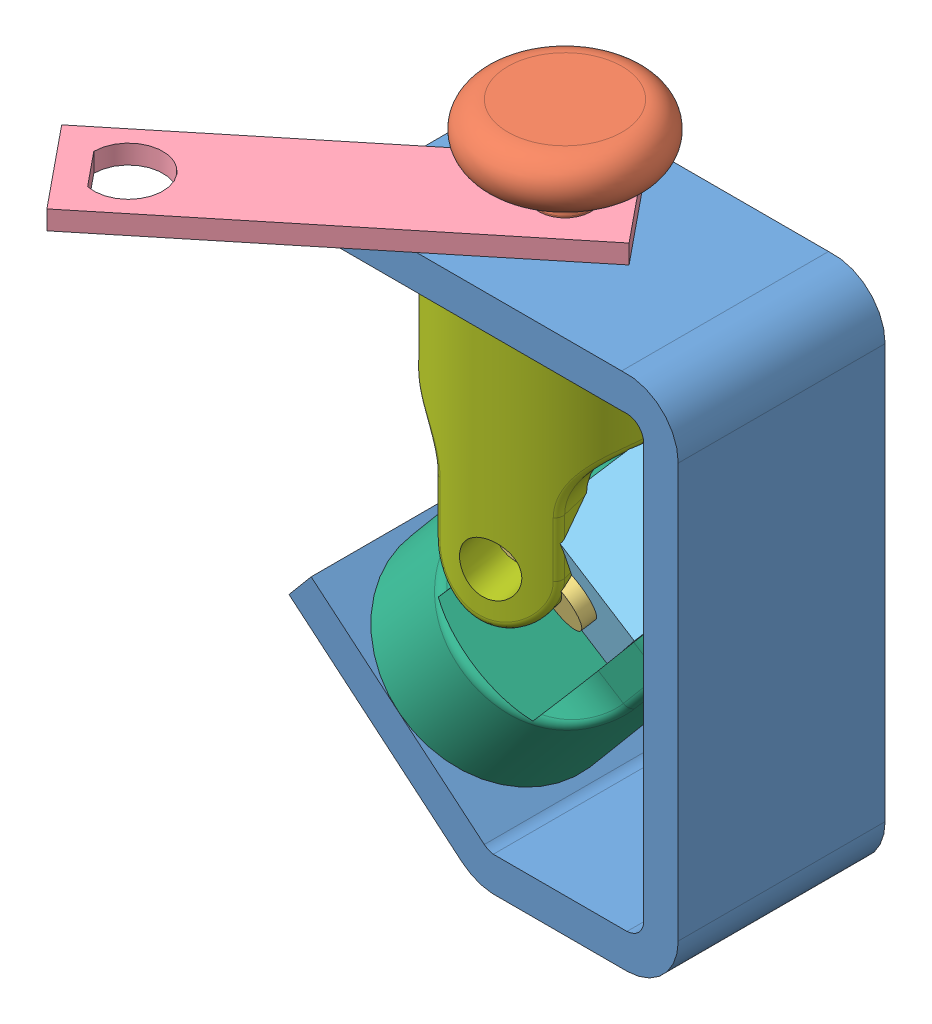
SolidWorks assembly Assem1, configuration Default. Lengths in mm.
Overall size (97.73 122.57 72.66).
10 component instances, 7 part files, 20 mates.
Components (placement in the parent):
- Taran (3)-1: Taran (3) [Default] at (30.1828 89.4752 48.9839) size (71.68 95.29 38.1)
- Taran (4)-1: Taran (4) [Default] at (54.6828 86.6252 68.0339) x (-0.908705 0 -0.41744) z (0.41744 0 -0.908705) size (30.54 21.91 30.54)
- Taran (6)-1: Taran (6) [Default] at (65.1662 39.4433 79.6676) x (-0.540596 -0.746524 -0.387889) z (0.177871 0.349222 -0.920003) size (9.52 9.52 12.7)
- Taran (7)-1: Taran (7) [Default] at (55.909 89.4752 54.7431) x (-0.77497 0 0.631998) z (-0.631998 0 -0.77497) size (76.2 3.5 19.05)
- Taran (8)-1: Taran (8) [Default] at (73.7349 50.8145 71.8958) x (0.177871 0.349222 -0.920003) z (-0.762547 0.639853 0.095452) size (20.32 20.32 20.32)
- t9-1: t9 [Default] at (54.7654 28.7835 68.0339) x (0.07312 -0.061355 0.995434) z (0.762547 -0.639853 -0.095452) size (38.96 67.63 38.1)
- t11-1: t11 [Default] at (54.6828 64.7052 68.0339) x (0.972965 0 -0.230951) z (0.230951 0 0.972965) size (38.96 47.63 38.1)
- Taran (6)-2: Taran (6) [Default] at (69.6841 48.3135 56.2995) x (-0.330869 0.901704 0.278307) z (-0.177871 -0.349222 0.920003) size (9.52 9.52 12.7)
- Taran (6)-3: Taran (6) [Default] at (54.0962 45.0252 65.5626) x (-0.665713 -0.729285 0.158019) z (0.230951 0 0.972965) size (9.52 9.52 12.7)
- Taran (6)-4: Taran (6) [Default] at (55.2694 45.0252 70.5052) x (-0.342478 -0.936002 0.081293) z (-0.230951 0 -0.972965) size (9.52 9.52 12.7)
Mates (geometry in assembly coordinates):
- Concentric1: concentric aligned: cylinder of Taran (4)-1 through (54.6828 86.6252 68.0339) axis (0 -1 0) radius 2.38; cylinder of Taran (7)-1 through (54.6828 92.9752 68.0339) axis (0 -1 0) radius 2.37
- Concentric2: concentric aligned: circle of Taran (3)-1; circle of t9-1
- Coincident1: coincident anti-aligned: plane of Taran (3)-1 through (58.8666 1.2966 87.0839) normal (0.642788 0.766044 0); circle of t9-1
- Concentric3: concentric aligned: circle of Taran (3)-1; circle of Taran (7)-1
- Concentric4: concentric aligned: circle of Taran (3)-1; circle of Taran (7)-1
- Coincident2: coincident anti-aligned: plane of Taran (3)-1 through (30.1828 89.4752 87.0839) normal (0 1 0); plane of Taran (7)-1 through (55.909 89.4752 54.7431) normal (0 -1 0)
- Concentric5: concentric aligned: cylinder of Taran (4)-1 through (54.6828 86.6252 68.0339) axis (0 -1 0) radius 2.38; cylinder of Taran (7)-1 through (54.6828 92.9752 68.0339) axis (0 -1 0) radius 2.37
- Coincident3: coincident anti-aligned: plane of Taran (4)-1 through (52.5201 92.9752 67.0404) normal (0 -1 0); plane of Taran (7)-1 through (55.909 92.9752 54.7431) normal (0 1 0)
- Concentric8: concentric aligned: circle of Taran (8)-1; circle of t9-1
- Concentric9: concentric anti-aligned: circle of Taran (8)-1; circle of t9-1
- Coincident5: coincident anti-aligned: plane of Taran (8)-1 through (55.1556 46.9531 55.7945) normal (-0.762547 0.639853 0.095452); circle of t9-1
- Concentric11: concentric aligned: circle of Taran (6)-1; circle of Taran (8)-1
- Concentric12: concentric aligned: circle of t11-1; circle of Taran (3)-1
- Coincident7: coincident anti-aligned: plane of Taran (3)-1 through (30.1828 83.1252 87.0839) normal (0 -1 0); plane of t11-1 through (54.6828 83.1252 68.0339) normal (0 1 0)
- Concentric13: concentric anti-aligned: circle of Taran (8)-1; circle of Taran (6)-2
- Coincident8: coincident anti-aligned: plane of Taran (6)-1 through (67.4252 43.8784 67.9835) normal (0.177871 0.349222 -0.920003); plane of Taran (6)-2 through (67.4252 43.8784 67.9835) normal (-0.177871 -0.349222 0.920003)
- Coincident9: coincident anti-aligned: plane of t11-1 through (57.0293 45.0252 77.9192) normal (-0.230951 0 -0.972965); plane of Taran (6)-3 through (57.0293 45.0252 77.9192) normal (0.230951 0 0.972965)
- Concentric14: concentric aligned: circle of t11-1; circle of Taran (6)-3
- Coincident10: coincident anti-aligned: plane of t11-1 through (52.3363 45.0252 58.1486) normal (0.230951 0 0.972965); circle of Taran (6)-4
- Concentric15: concentric anti-aligned: circle of t11-1; circle of Taran (6)-4
